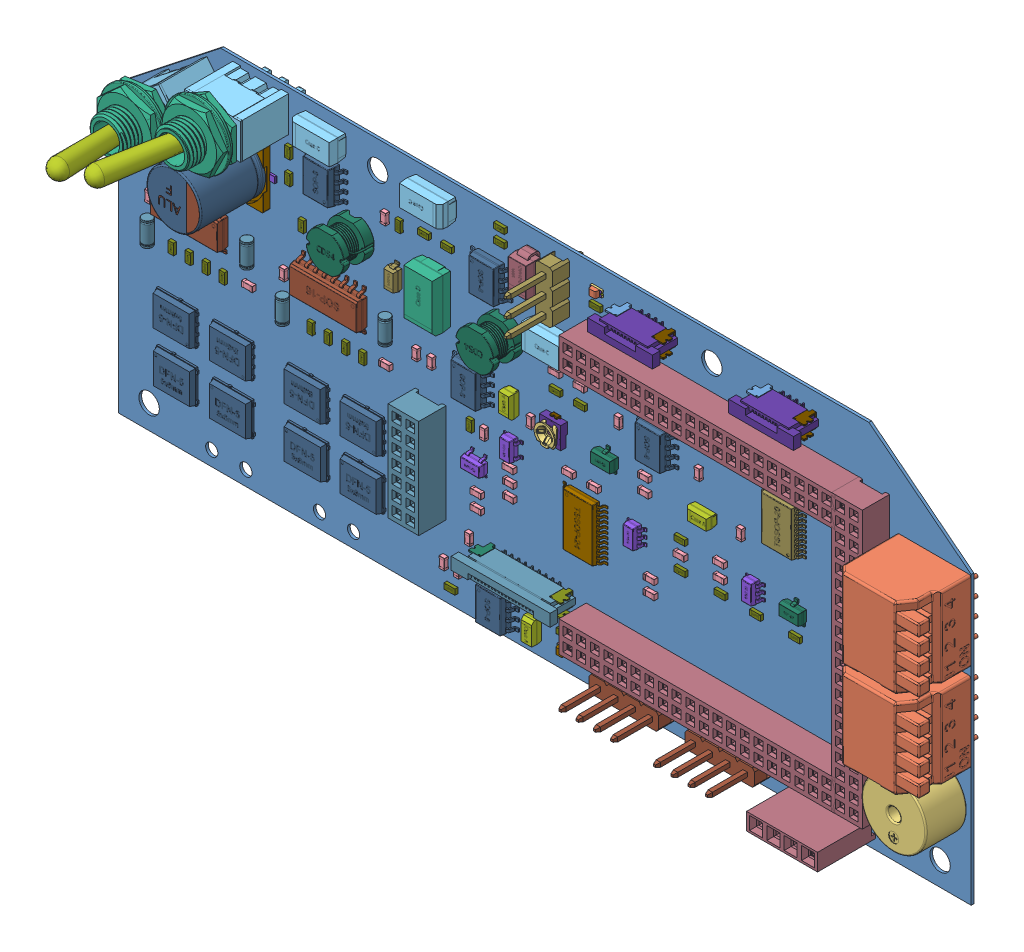
SolidWorks assembly 主板_V1.0, configuration Default. Lengths in mm.
Overall size (126.34 56.68 27.25).
280 component instances, 55 part files, 0 mates.
Components (placement in the parent):
- Board主板_V1.0-1: Board主板_V1.0 [默认] at (0 0 -0.3912) size (125 53.81 0.39)
- S4主板_V1.0-1: S4主板_V1.0 [默认] at origin size (12.1 11.72 11.5)
  - Switch-Piano-DIP-4-1: Switch-Piano-DIP-4 [默认] at (109.7535 13.9265 0.1) x (0 1 0) z (1 0 0) size (11.72 11.5 12.1)
- LS主板_V1.0-1: LS主板_V1.0 [默认] at origin size (9.5 9.5 8)
  - Buzzer_9.5x6-1: Buzzer_9.5x6 [默认] at (115.1492 8.3052 0) x (0 1 0) z (0 0 1) size (9.5 9.5 8)
- C1主板_V1.0-1: C1主板_V1.0 [默认] at origin size (1.6 0.8 0.6)
  - CAP-0603-1: CAP-0603 [默认] at (84.0359 19.9384 0) size (1.6 0.8 0.6)
- C2主板_V1.0-1: C2主板_V1.0 [默认] at origin size (1.6 0.8 0.6)
  - CAP-0603-1: CAP-0603 [默认] at (83.9961 21.94 0) size (1.6 0.8 0.6)
- C3主板_V1.0-1: C3主板_V1.0 [默认] at origin size (1.6 0.8 0.6)
  - CAP-0603-1: CAP-0603 [默认] at (53.135 18.5118 0) size (1.6 0.8 0.6)
- C4主板_V1.0-1: C4主板_V1.0 [默认] at origin size (0.8 1.6 0.6)
  - CAP-0603-1: CAP-0603 [默认] at (49.3838 21.0686 0) x (0 -1 0) z (0 0 1) size (1.6 0.8 0.6)
- C5主板_V1.0-1: C5主板_V1.0 [默认] at origin size (1.6 0.8 0.6)
  - CAP-0603-1: CAP-0603 [默认] at (61.8473 22.2703 0) size (1.6 0.8 0.6)
- C6主板_V1.0-1: C6主板_V1.0 [默认] at origin size (1.6 0.8 0.6)
  - CAP-0603-1: CAP-0603 [默认] at (48.4107 10.9419 0) size (1.6 0.8 0.6)
- C7主板_V1.0-1: C7主板_V1.0 [默认] at origin size (1.6 0.8 0.6)
  - CAP-0603-1: CAP-0603 [默认] at (48.4107 12.9739 0) size (1.6 0.8 0.6)
- C9主板_V1.0-1: C9主板_V1.0 [默认] at origin size (1.6 0.8 0.6)
  - CAP-0603-1: CAP-0603 [默认] at (73.8138 12.8609 0) x (-1 0 0) z (0 0 1) size (1.6 0.8 0.6)
- C10主板_V1.0-1: C10主板_V1.0 [默认] at origin size (1.6 0.8 0.6)
  - CAP-0603-1: CAP-0603 [默认] at (65.5303 22.2703 0) size (1.6 0.8 0.6)
- C11主板_V1.0-1: C11主板_V1.0 [默认] at origin size (1.6 0.8 0.6)
  - CAP-0603-1: CAP-0603 [默认] at (78.1939 19.9384 0) size (1.6 0.8 0.6)
- C12主板_V1.0-1: C12主板_V1.0 [默认] at origin size (1.6 0.8 0.6)
  - CAP-0603-1: CAP-0603 [默认] at (53.1606 16.6494 0) x (-1 0 0) z (0 0 1) size (1.6 0.8 0.6)
- C13主板_V1.0-1: C13主板_V1.0 [默认] at origin size (1.6 0.8 0.6)
  - CAP-0603-1: CAP-0603 [默认] at (53.1606 14.7869 0) x (-1 0 0) z (0 0 1) size (1.6 0.8 0.6)
- C14主板_V1.0-1: C14主板_V1.0 [默认] at origin size (1.6 0.8 0.6)
  - CAP-0603-1: CAP-0603 [默认] at (72.9472 25.3279 0) x (-1 0 0) z (0 0 1) size (1.6 0.8 0.6)
- C15主板_V1.0-1: C15主板_V1.0 [默认] at origin size (1.6 0.8 0.6)
  - CAP-0603-1: CAP-0603 [默认] at (72.9472 27.3235 0) x (-1 0 0) z (0 0 1) size (1.6 0.8 0.6)
- C16主板_V1.0-1: C16主板_V1.0 [默认] at origin size (6 3.2 2.5)
  - CaseC_6032-28-1: CaseC_6032-28 [默认] at (59.5741 38.0994 0) x (1 0 0) z (0 -1 0) size (6 2.5 3.2)
- C17主板_V1.0-1: C17主板_V1.0 [默认] at origin size (1.6 0.8 0.6)
  - CAP-0603-1: CAP-0603 [默认] at (59.8805 34.0662 0) x (-1 0 0) z (0 0 1) size (1.6 0.8 0.6)
- C18主板_V1.0-1: C18主板_V1.0 [默认] at origin size (6 3.2 2.5)
  - CaseC_6032-28-1: CaseC_6032-28 [默认] at (42.1242 47.2178 0) x (-1 0 0) z (0 1 0) size (6 2.5 3.2)
- C19主板_V1.0-1: C19主板_V1.0 [默认] at origin size (0.8 1.6 0.6)
  - CAP-0603-1: CAP-0603 [默认] at (34.855 41.1608 0) x (0 -1 0) z (0 0 1) size (1.6 0.8 0.6)
- C20主板_V1.0-1: C20主板_V1.0 [默认] at origin size (6 3.2 2.5)
  - CaseC_6032-28-1: CaseC_6032-28 [默认] at (25.9589 47.218 0) x (1 0 0) z (0 -1 0) size (6 2.5 3.2)
- C21主板_V1.0-1: C21主板_V1.0 [默认] at origin size (4.3 7.3 2.8)
  - CaseD_7343-31-1: CaseD_7343-31 [默认] at (42.2148 35.4076 0) x (0 1 0) z (1 0 0) size (7.3 2.8 4.3)
- C22主板_V1.0-1: C22主板_V1.0 [默认] at origin size (0.8 1.6 0.6)
  - CAP-0603-1: CAP-0603 [默认] at (43.4872 1.6835 0) x (0 -1 0) z (0 0 1) size (1.6 0.8 0.6)
- C23主板_V1.0-1: C23主板_V1.0 [默认] at origin size (0.8 1.6 0.6)
  - CAP-0603-1: CAP-0603 [默认] at (45.57 1.6835 0) x (0 -1 0) z (0 0 1) size (1.6 0.8 0.6)
- C24主板_V1.0-1: C24主板_V1.0 [默认] at origin size (0.8 1.6 0.6)
  - CAP-0603-1: CAP-0603 [默认] at (47.1994 6.616 0) x (0 -1 0) z (0 0 1) size (1.6 0.8 0.6)
- C25主板_V1.0-1: C25主板_V1.0 [默认] at origin size (0.8 1.6 0.6)
  - CAP-0603-1: CAP-0603 [默认] at (39.4668 26.2255 0) x (0 -1 0) z (0 0 1) size (1.6 0.8 0.6)
- C26主板_V1.0-1: C26主板_V1.0 [默认] at origin size (0.8 1.6 0.6)
  - CAP-0603-1: CAP-0603 [默认] at (41.6766 26.2255 0) x (0 -1 0) z (0 0 1) size (1.6 0.8 0.6)
- C27主板_V1.0-1: C27主板_V1.0 [默认] at origin size (0.8 1.6 0.6)
  - CAP-0603-1: CAP-0603 [默认] at (56.2261 25.9706 0) x (0 1 0) z (0 0 1) size (1.6 0.8 0.6)
- C28主板_V1.0-1: C28主板_V1.0 [默认] at origin size (0.8 1.6 0.6)
  - CAP-0603-1: CAP-0603 [默认] at (69.1039 32.3714 0) x (0 1 0) z (0 0 1) size (1.6 0.8 0.6)
- C29主板_V1.0-1: C29主板_V1.0 [默认] at origin size (0.8 1.6 0.6)
  - CAP-0603-1: CAP-0603 [默认] at (80.8641 31.7112 0) x (0 1 0) z (0 0 1) size (1.6 0.8 0.6)
- C30主板_V1.0-1: C30主板_V1.0 [默认] at origin size (1.6 3.2 1.6)
  - CaseA_3216-18-1: CaseA_3216-18 [默认] at (56.8961 0.2031 0) x (0 -1 0) z (-1 0 0) size (3.2 1.6 1.6)
- C31主板_V1.0-1: C31主板_V1.0 [默认] at origin size (1.6 3.2 1.6)
  - CaseA_3216-18-1: CaseA_3216-18 [默认] at (53.5541 27.152 0) x (0 1 0) z (1 0 0) size (3.2 1.6 1.6)
- C32主板_V1.0-1: C32主板_V1.0 [默认] at origin size (3.2 1.6 1.6)
  - CaseA_3216-18-1: CaseA_3216-18 [默认] at (81.6974 26.898 0) x (1 0 0) z (0 -1 0) size (3.2 1.6 1.6)
- C33主板_V1.0-1: C33主板_V1.0 [默认] at origin size (9.9 8.3 10.2)
  - ALU-F_8.0x8.3x10.2-1: ALU-F_8.0x8.3x10.2 [默认] at (13.7778 37.769 0) x (-1 0 0) z (0 0 1) size (9.9 8.3 10.2)
    - User_Library-ALU-F_Pins_1-1: User_Library-ALU-F_Pins_1 [默认] at origin size (9.9 0.9 0.4)
    - User_Library-ALU-F_Fuss_1-1: User_Library-ALU-F_Fuss_1 [默认] at origin size (8.3 8.3 1)
    - User_Library-ALU-F_K_X_F6rper_1-1: User_Library-ALU-F_K_X_F6rper_1 [默认] at origin size (8 8 9.5)
    - User_Library-ALU-F_Beschriftung_1-1: User_Library-ALU-F_Beschriftung_1 [默认] at origin size (5.99 6.58 0.06)
- C34主板_V1.0-1: C34主板_V1.0 [默认] at origin size (1.6 0.8 0.6)
  - CAP-0603-1: CAP-0603 [默认] at (14.9082 22.5244 0) x (-1 0 0) z (0 0 1) size (1.6 0.8 0.6)
- C35主板_V1.0-1: C35主板_V1.0 [默认] at origin size (0.8 1.6 0.6)
  - CAP-0603-1: CAP-0603 [默认] at (0.2953 26.641 0) x (0 1 0) z (0 0 1) size (1.6 0.8 0.6)
- C36主板_V1.0-1: C36主板_V1.0 [默认] at origin size (1.6 0.8 0.6)
  - CAP-0603-1: CAP-0603 [默认] at (34.9742 22.5244 0) x (-1 0 0) z (0 0 1) size (1.6 0.8 0.6)
- C37主板_V1.0-1: C37主板_V1.0 [默认] at origin size (0.8 1.6 0.6)
  - CAP-0603-1: CAP-0603 [默认] at (20.0311 26.641 0) x (0 1 0) z (0 0 1) size (1.6 0.8 0.6)
- C38主板_V1.0-1: C38主板_V1.0 [默认] at origin size (0.8 1.6 0.6)
  - CAP-0603-1: CAP-0603 [默认] at (87.0363 27.1392 0) x (0 1 0) z (0 0 1) size (1.6 0.8 0.6)
- C39主板_V1.0-1: C39主板_V1.0 [默认] at origin size (1.6 0.8 0.6)
  - CAP-0603-1: CAP-0603 [默认] at (63.5128 34.0662 0) x (-1 0 0) z (0 0 1) size (1.6 0.8 0.6)
- D1主板_V1.0-1: D1主板_V1.0 [默认] at origin size (1.77 3.74 1.47)
  - Diode-SOD123-1: Diode-SOD123 [默认] at (36.4235 34.3916 0) x (0 1 0) z (0 0 1) size (3.74 1.77 1.47)
- D2主板_V1.0-1: D2主板_V1.0 [默认] at origin size (2.8 5.5 2.58)
  - Diode-SMA-1: Diode-SMA [默认] at (56.523 45.4146 0) x (0 1 0) z (0 0 1) size (5.5 2.8 2.58)
- D3主板_V1.0-1: D3主板_V1.0 [默认] at origin size (1.5 3.5 1.5)
  - Diode-SMD-1206-1: Diode-SMD-1206 [默认] at (15.0732 27.0249 0.74) x (0 1 0) z (0 0 1) size (3.5 1.5 1.5)
- D4主板_V1.0-1: D4主板_V1.0 [默认] at origin size (1.5 3.5 1.5)
  - Diode-SMD-1206-1: Diode-SMD-1206 [默认] at (0.4682 22.4783 0.74) x (0 -1 0) z (0 0 1) size (3.5 1.5 1.5)
- D5主板_V1.0-1: D5主板_V1.0 [默认] at origin size (1.5 3.5 1.5)
  - Diode-SMD-1206-1: Diode-SMD-1206 [默认] at (35.3276 27.4059 0.74) x (0 1 0) z (0 0 1) size (3.5 1.5 1.5)
- D6主板_V1.0-1: D6主板_V1.0 [默认] at origin size (1.5 3.5 1.5)
  - Diode-SMD-1206-1: Diode-SMD-1206 [默认] at (20.2802 22.4783 0.74) x (0 -1 0) z (0 0 1) size (3.5 1.5 1.5)
- L2主板_V1.0-1: L2主板_V1.0 [默认] at origin size (5.51 5.35 4.58)
  - Inductor-CD-54-1: Inductor-CD-54 [默认] at (52.2523 35.0283 0) x (-1 0 0) z (0 1 0) size (5.51 4.58 5.35)
- LED1主板_V1.0-1: LED1主板_V1.0 [默认] at origin size (1.7 0.9 0.9)
  - LED-GREEN-0603-1: LED-GREEN-0603 [默认] at (65.797 47.2433 0) x (0 -1 0) z (0 0 1) size (0.9 1.7 0.9)
    - User_Library-LTST-C190GKT_Pad005-1: User_Library-LTST-C190GKT_Pad005 [默认] at origin size (0.35 0.15 0.31)
    - User_Library-LTST-C190GKT_Pad001-1: User_Library-LTST-C190GKT_Pad001 [默认] at origin size (0.9 1.7 0.01)
    - User_Library-LTST-C190GKT_Pad004-1: User_Library-LTST-C190GKT_Pad004 [默认] at origin size (0.35 0.15 0.31)
    - User_Library-LTST-C190GKT_Pad003-1: User_Library-LTST-C190GKT_Pad003 [默认] at origin size (0.8 1.7 0.02)
    - User_Library-LTST-C190GKT_Lens-1: User_Library-LTST-C190GKT_Lens [默认] at origin size (0.9 1.15 0.6)
    - User_Library-LTST-C190GKT_Pad-1: User_Library-LTST-C190GKT_Pad [默认] at origin size (0.9 1.7 0.28)
- LED2主板_V1.0-1: LED2主板_V1.0 [默认] at origin size (1.7 0.9 0.9)
  - LED-BLUE-0603-1: LED-BLUE-0603 [默认] at (60.9346 -0.73 0) x (0 -1 0) z (0 0 1) size (0.9 1.7 0.9)
    - User_Library-LTST-C190TBKT_Pad-1: User_Library-LTST-C190TBKT_Pad [默认] at origin size (0.9 1.7 0.28)
    - User_Library-LTST-C190TBKT_Pad005-1: User_Library-LTST-C190TBKT_Pad005 [默认] at origin size (0.35 0.15 0.31)
    - User_Library-LTST-C190TBKT_Pad001-1: User_Library-LTST-C190TBKT_Pad001 [默认] at origin size (0.9 1.7 0.01)
    - User_Library-LTST-C190TBKT_Pad004-1: User_Library-LTST-C190TBKT_Pad004 [默认] at origin size (0.35 0.15 0.31)
    - User_Library-LTST-C190TBKT_Pad003-1: User_Library-LTST-C190TBKT_Pad003 [默认] at origin size (0.8 1.7 0.02)
    - User_Library-LTST-C190TBKT_Lens-1: User_Library-LTST-C190TBKT_Lens [默认] at origin size (0.9 1.15 0.6)
- MOS1主板_V1.0-1: MOS1主板_V1.0 [默认] at origin size (6.15 5.15 1.02)
  - DFN-5-5x6mm-1: DFN-5-5x6mm [默认] at (15.2407 14.9384 0) x (0 1 0) z (0 0 1) size (5.15 6.15 1.02)
- MOS2主板_V1.0-1: MOS2主板_V1.0 [默认] at origin size (6.15 5.15 1.02)
  - DFN-5-5x6mm-1: DFN-5-5x6mm [默认] at (7.0111 14.9384 0) x (0 1 0) z (0 0 1) size (5.15 6.15 1.02)
- MOS3主板_V1.0-1: MOS3主板_V1.0 [默认] at origin size (6.15 5.15 1.02)
  - DFN-5-5x6mm-1: DFN-5-5x6mm [默认] at (9.7187 3.8068 0) x (0 -1 0) z (0 0 1) size (5.15 6.15 1.02)
- MOS4主板_V1.0-1: MOS4主板_V1.0 [默认] at origin size (6.15 5.15 1.02)
  - DFN-5-5x6mm-1: DFN-5-5x6mm [默认] at (1.4891 3.8068 0) x (0 -1 0) z (0 0 1) size (5.15 6.15 1.02)
- MOS6主板_V1.0-1: MOS6主板_V1.0 [默认] at origin size (6.15 5.15 1.02)
  - DFN-5-5x6mm-1: DFN-5-5x6mm [默认] at (26.1969 14.9384 0) x (0 1 0) z (0 0 1) size (5.15 6.15 1.02)
- MOS5主板_V1.0-1: MOS5主板_V1.0 [默认] at origin size (6.15 5.15 1.02)
  - DFN-5-5x6mm-1: DFN-5-5x6mm [默认] at (34.3923 14.9384 0) x (0 1 0) z (0 0 1) size (5.15 6.15 1.02)
- MOS7主板_V1.0-1: MOS7主板_V1.0 [默认] at origin size (6.15 5.15 1.02)
  - DFN-5-5x6mm-1: DFN-5-5x6mm [默认] at (28.8703 3.8068 0) x (0 -1 0) z (0 0 1) size (5.15 6.15 1.02)
- MOS8主板_V1.0-1: MOS8主板_V1.0 [默认] at origin size (6.15 5.15 1.02)
  - DFN-5-5x6mm-1: DFN-5-5x6mm [默认] at (20.6749 3.8068 0) x (0 -1 0) z (0 0 1) size (5.15 6.15 1.02)
- P1主板_V1.0-1: P1主板_V1.0 [默认] at origin size (10.16 2.5 11.2)
  - Pin-Header-2.54-Single-4-1: Pin-Header-2.54-Single-4 [默认] at (72.3233 -0.6114 0.1) x (-1 0 0) z (0 -1 0) size (10.16 11.2 2.5)
- P2主板_V1.0-1: P2主板_V1.0 [默认] at origin size (10.16 2.5 11.2)
  - Pin-Header-2.54-Single-4-1: Pin-Header-2.54-Single-4 [默认] at (86.2091 -0.6854 0.1) x (1 0 0) z (0 1 0) size (10.16 11.2 2.5)
- P4主板_V1.0-1: P4主板_V1.0 [默认] at origin size (2.5 7.62 11.2)
  - Pin-Header-2.54-Single-3-1: Pin-Header-2.54-Single-3 [默认] at (60.5173 45.2891 0.1) x (0 1 0) z (-1 0 0) size (7.62 11.2 2.5)
- P7主板_V1.0-1: P7主板_V1.0 [默认] at origin size (10.41 2.5 11.7)
  - Female-Header-2.54-Single-4-1: Female-Header-2.54-Single-4 [默认] at (101.4351 -0.6431 0.15) x (-1 0 0) z (0 1 0) size (10.41 11.7 2.5)
- P8主板_V1.0-1: P8主板_V1.0 [默认] at origin size (4.5 14.5 6.8)
  - Female-Header-2.00-Double-14-1: Female-Header-2.00-Double-14 [默认] at (41.4258 14.3265 0.15) x (0 -1 0) z (-1 0 0) size (14.5 6.8 4.5)
- Q1主板_V1.0-1: Q1主板_V1.0 [默认] at origin size (3.01 3 1.3)
  - SOT323-3-1: SOT323-3 [默认] at (67.3957 26.7962 0) x (1 0 0) z (0 -1 0) size (3.01 1.3 3)
- Q2主板_V1.0-1: Q2主板_V1.0 [默认] at origin size (3.01 3 1.3)
  - SOT323-3-1: SOT323-3 [默认] at (95.0055 21.2336 0) x (1 0 0) z (0 -1 0) size (3.01 1.3 3)
- R1主板_V1.0-1: R1主板_V1.0 [默认] at origin size (1.6 0.8 0.46)
  - RES-0603-1: RES-0603 [默认] at (84.0612 17.9323 0.24) x (0 -1 0) z (-1 0 0) size (0.8 0.46 1.6)
- R2主板_V1.0-1: R2主板_V1.0 [默认] at origin size (1.6 0.8 0.46)
  - RES-0603-1: RES-0603 [默认] at (64.8952 -0.7374 0.24) x (0 -1 0) z (-1 0 0) size (0.8 0.46 1.6)
- R3主板_V1.0-1: R3主板_V1.0 [默认] at origin size (1.6 0.8 0.46)
  - RES-0603-1: RES-0603 [默认] at (93.7499 -0.7375 0.24) x (0 1 0) z (1 0 0) size (0.8 0.46 1.6)
- R4主板_V1.0-1: R4主板_V1.0 [默认] at origin size (1.6 0.8 0.46)
  - RES-0603-1: RES-0603 [默认] at (89.2936 17.9323 0.24) x (0 -1 0) z (-1 0 0) size (0.8 0.46 1.6)
- R5主板_V1.0-1: R5主板_V1.0 [默认] at origin size (3.1 3.69 2.19)
  - User_Library-PVZ3A-1: User_Library-PVZ3A [默认] at (59.8788 26.7875 0) size (3.1 3.69 2.19)
    - User_Library-PVZ3A_PVZ3A_base_По_умолчанию-1: User_Library-PVZ3A_PVZ3A_base_По_умолчанию [默认] at origin size (3.1 3.2 1)
    - User_Library-PVZ3A_Pin1_По_умолчанию-1: User_Library-PVZ3A_Pin1_По_умолчанию [默认] at (0 1.14 0) size (1 0.7 0.65)
    - User_Library-PVZ3A_Pin2_По_умолчанию-1: User_Library-PVZ3A_Pin2_По_умолчанию [默认] at (0.875 -1.15 0) x (-1 0 0) z (0 0 1) size (0.75 0.7 0.65)
    - User_Library-PVZ3A_Pin2_По_умолчанию_2-1: User_Library-PVZ3A_Pin2_По_умолчанию_2 [默认] at (-0.875 -1.15 0) x (-1 0 0) z (0 0 1) size (0.75 0.7 0.65)
    - User_Library-PVZ3A_PVZ3A_res_По_умолчанию-1: User_Library-PVZ3A_PVZ3A_res_По_умолчанию [默认] at (0 0 0.9) size (3 3.08 1.33)
    - User_Library-PVZ3A_PVZ3A_con_По_умолчанию-1: User_Library-PVZ3A_PVZ3A_con_По_умолчанию [默认] at (0 0 1.22) size (0.58 0.58 0.75)
- R6主板_V1.0-1: R6主板_V1.0 [默认] at origin size (1.6 0.8 0.46)
  - RES-0603-1: RES-0603 [默认] at (78.1794 21.894 0.24) x (0 -1 0) z (-1 0 0) size (0.8 0.46 1.6)
- R7主板_V1.0-1: R7主板_V1.0 [默认] at origin size (1.6 0.8 0.46)
  - RES-0603-1: RES-0603 [默认] at (78.2192 17.9323 0.24) x (0 -1 0) z (-1 0 0) size (0.8 0.46 1.6)
- R8主板_V1.0-1: R8主板_V1.0 [默认] at origin size (0.8 1.6 0.46)
  - RES-0603-1: RES-0603 [默认] at (20.7266 39.0272 0.24) x (-1 0 0) z (0 1 0) size (0.8 0.46 1.6)
- R9主板_V1.0-1: R9主板_V1.0 [默认] at origin size (1.6 0.8 0.46)
  - RES-0603-1: RES-0603 [默认] at (51.727 48.2592 0.24) x (0 -1 0) z (-1 0 0) size (0.8 0.46 1.6)
- R10主板_V1.0-1: R10主板_V1.0 [默认] at origin size (1.6 0.8 0.46)
  - RES-0603-1: RES-0603 [默认] at (51.727 46.4057 0.24) x (0 -1 0) z (-1 0 0) size (0.8 0.46 1.6)
- R11主板_V1.0-1: R11主板_V1.0 [默认] at origin size (0.8 1.6 0.46)
  - RES-0603-1: RES-0603 [默认] at (20.7265 42.4052 0.24) x (1 0 0) z (0 -1 0) size (0.8 0.46 1.6)
- R12主板_V1.0-1: R12主板_V1.0 [默认] at origin size (1.6 0.8 0.46)
  - RES-0603-1: RES-0603 [默认] at (43.9802 41.9355 0.24) x (0 1 0) z (1 0 0) size (0.8 0.46 1.6)
- R13主板_V1.0-1: R13主板_V1.0 [默认] at origin size (0.8 1.6 0.46)
  - RES-0603-1: RES-0603 [默认] at (36.8807 41.1355 0.24) x (-1 0 0) z (0 1 0) size (0.8 0.46 1.6)
- R14主板_V1.0-1: R14主板_V1.0 [默认] at origin size (1.6 0.8 0.46)
  - RES-0603-1: RES-0603 [默认] at (40.602 41.9355 0.24) x (0 1 0) z (1 0 0) size (0.8 0.46 1.6)
- R15主板_V1.0-1: R15主板_V1.0 [默认] at origin size (1.6 0.8 0.46)
  - RES-0603-1: RES-0603 [默认] at (44.488 -1.1431 0.24) x (0 -1 0) z (-1 0 0) size (0.8 0.46 1.6)
- R16主板_V1.0-1: R16主板_V1.0 [默认] at origin size (1.6 0.8 0.46)
  - RES-0603-1: RES-0603 [默认] at (65.7725 45.3128 0.24) x (0 -1 0) z (-1 0 0) size (0.8 0.46 1.6)
- R17主板_V1.0-1: R17主板_V1.0 [默认] at origin size (1.6 0.8 0.46)
  - RES-0603-1: RES-0603 [默认] at (60.9472 1.4223 0.24) x (0 -1 0) z (-1 0 0) size (0.8 0.46 1.6)
- R18主板_V1.0-1: R18主板_V1.0 [默认] at origin size (0.8 1.6 0.46)
  - RES-0603-1: RES-0603 [默认] at (47.3312 21.0433 0.24) x (-1 0 0) z (0 1 0) size (0.8 0.46 1.6)
- R19主板_V1.0-1: R19主板_V1.0 [默认] at origin size (0.8 1.6 0.46)
  - RES-0603-1: RES-0603 [默认] at (11.1361 21.7298 0.24) x (-1 0 0) z (0 1 0) size (0.8 0.46 1.6)
- R20主板_V1.0-1: R20主板_V1.0 [默认] at origin size (0.8 1.6 0.46)
  - RES-0603-1: RES-0603 [默认] at (8.6385 21.7298 0.24) x (-1 0 0) z (0 1 0) size (0.8 0.46 1.6)
- R21主板_V1.0-1: R21主板_V1.0 [默认] at origin size (1.6 0.8 0.46)
  - RES-0603-1: RES-0603 [默认] at (2.832 33.8838 0.24) x (0 -1 0) z (-1 0 0) size (0.8 0.46 1.6)
- R22主板_V1.0-1: R22主板_V1.0 [默认] at origin size (1.6 0.8 0.46)
  - RES-0603-1: RES-0603 [默认] at (6.2612 33.8837 0.24) x (0 1 0) z (1 0 0) size (0.8 0.46 1.6)
- R23主板_V1.0-1: R23主板_V1.0 [默认] at origin size (0.8 1.6 0.46)
  - RES-0603-1: RES-0603 [默认] at (6.1408 21.7298 0.24) x (-1 0 0) z (0 1 0) size (0.8 0.46 1.6)
- R24主板_V1.0-1: R24主板_V1.0 [默认] at origin size (0.8 1.6 0.46)
  - RES-0603-1: RES-0603 [默认] at (3.6432 21.7298 0.24) x (-1 0 0) z (0 1 0) size (0.8 0.46 1.6)
- R25主板_V1.0-1: R25主板_V1.0 [默认] at origin size (0.8 1.6 0.46)
  - RES-0603-1: RES-0603 [默认] at (31.5831 21.7291 0.24) x (-1 0 0) z (0 1 0) size (0.8 0.46 1.6)
- R26主板_V1.0-1: R26主板_V1.0 [默认] at origin size (0.8 1.6 0.46)
  - RES-0603-1: RES-0603 [默认] at (29.0479 21.7298 0.24) x (-1 0 0) z (0 1 0) size (0.8 0.46 1.6)
- R27主板_V1.0-1: R27主板_V1.0 [默认] at origin size (0.8 1.6 0.46)
  - RES-0603-1: RES-0603 [默认] at (22.6932 34.0481 0.24) x (-1 0 0) z (0 1 0) size (0.8 0.46 1.6)
- R28主板_V1.0-1: R28主板_V1.0 [默认] at origin size (0.8 1.6 0.46)
  - RES-0603-1: RES-0603 [默认] at (24.9793 34.048 0.24) x (1 0 0) z (0 -1 0) size (0.8 0.46 1.6)
- R29主板_V1.0-1: R29主板_V1.0 [默认] at origin size (0.8 1.6 0.46)
  - RES-0603-1: RES-0603 [默认] at (26.5127 21.7298 0.24) x (-1 0 0) z (0 1 0) size (0.8 0.46 1.6)
- R30主板_V1.0-1: R30主板_V1.0 [默认] at origin size (0.8 1.6 0.46)
  - RES-0603-1: RES-0603 [默认] at (23.9775 21.7298 0.24) x (-1 0 0) z (0 1 0) size (0.8 0.46 1.6)
- R31主板_V1.0-1: R31主板_V1.0 [默认] at origin size (1.6 0.8 0.46)
  - RES-0603-1: RES-0603 [默认] at (59.8803 31.6483 0.24) x (0 -1 0) z (-1 0 0) size (0.8 0.46 1.6)
- R32主板_V1.0-1: R32主板_V1.0 [默认] at origin size (1.6 0.8 0.46)
  - RES-0603-1: RES-0603 [默认] at (63.5126 31.6483 0.24) x (0 -1 0) z (-1 0 0) size (0.8 0.46 1.6)
- R33主板_V1.0-1: R33主板_V1.0 [默认] at origin size (1.6 0.8 0.46)
  - RES-0603-1: RES-0603 [默认] at (95.034 17.9323 0.24) x (0 -1 0) z (-1 0 0) size (0.8 0.46 1.6)
- S1主板_V1.0-1: S1主板_V1.0 [默认] at origin size (17.73 16.75 27.25)
  - SW-SMTS-102-1: SW-SMTS-102 [默认] at (10.2794 45.0706 -8.5) x (0.788011 0.615661 0) z (0 0 1) size (15.11 9.45 27.25)
    - SW-SMTS-102-1-1: SW-SMTS-102-1 [默认] at (-2.742 1.0938 9.095) size (8.2 5.35 10.79)
    - SW-SMTS-102-2-1: SW-SMTS-102-2 [默认] at (-2.742 1.0938 24.585) size (9.45 9.45 6.14)
    - SW-SMTS-102-3-1: SW-SMTS-102-3 [默认] at (-3.1483 1.0938 18.8532) x (-0.970296 0 -0.241922) z (0 1 0) size (10.65 19.74 3.81)
- S2主板_V1.0-1: S2主板_V1.0 [默认] at origin size (15.11 9.45 27.25)
  - SW-SMTS-102-1: SW-SMTS-102 [默认] at (14.2145 48.6156 -8.5) x (-1 0 0) z (0 0 1) size (15.11 9.45 27.25)
    - SW-SMTS-102-1-1: SW-SMTS-102-1 [默认] at (-2.742 1.0938 9.095) size (8.2 5.35 10.79)
    - SW-SMTS-102-2-1: SW-SMTS-102-2 [默认] at (-2.742 1.0938 24.585) size (9.45 9.45 6.14)
    - SW-SMTS-102-3-1: SW-SMTS-102-3 [默认] at (-3.1483 1.0938 18.8532) x (-0.970296 0 -0.241922) z (0 1 0) size (10.65 19.74 3.81)
- S3主板_V1.0-1: S3主板_V1.0 [默认] at origin size (12.1 11.72 11.5)
  - Switch-Piano-DIP-4-1: Switch-Piano-DIP-4 [默认] at (109.7535 26.7535 0.1) x (0 1 0) z (1 0 0) size (11.72 11.5 12.1)
- U1主板_V1.0-1: U1主板_V1.0 [默认] at origin size (2.8 2.9 1.45)
  - SOT23-5-1: SOT23-5 [默认] at (53.5011 21.4624 0) x (0 -1 0) z (0 0 1) size (2.9 2.8 1.45)
- U2主板_V1.0-1: U2主板_V1.0 [默认] at origin size (2.9 2.8 1.45)
  - SOT23-5-1: SOT23-5 [默认] at (48.4234 16.7355 0) size (2.9 2.8 1.45)
- U3主板_V1.0-1: U3主板_V1.0 [默认] at origin size (2.8 2.9 1.45)
  - SOT23-5-1: SOT23-5 [默认] at (88.9642 21.1066 0) x (0 1 0) z (0 0 1) size (2.9 2.8 1.45)
- U4主板_V1.0-1: U4主板_V1.0 [默认] at origin size (6.55 7.9 1.2)
  - TSSOP-24-1: TSSOP-24 [默认] at (64.0191 17.4492 0) x (0 -1 0) z (0 0 1) size (7.9 6.55 1.2)
- U5主板_V1.0-1: U5主板_V1.0 [默认] at origin size (2.8 2.9 1.45)
  - SOT23-5-1: SOT23-5 [默认] at (71.6304 19.4563 0) x (0 1 0) z (0 0 1) size (2.9 2.8 1.45)
- U6主板_V1.0-1: U6主板_V1.0 [默认] at origin size (6 4.9 1.75)
  - SOP-8-1: SOP-8 [默认] at (26.173 41.9601 0) x (0 1 0) z (0 0 1) size (4.9 6 1.75)
- U7主板_V1.0-1: U7主板_V1.0 [默认] at origin size (6 4.9 1.75)
  - SOP-8-1: SOP-8 [默认] at (50.3285 41.5536 0) x (0 -1 0) z (0 0 1) size (4.9 6 1.75)
- U8主板_V1.0-1: U8主板_V1.0 [默认] at origin size (6 4.9 1.75)
  - SOP-8-1: SOP-8 [默认] at (51.3191 0.2532 0) x (0 -1 0) z (0 0 1) size (4.9 6 1.75)
- U9主板_V1.0-1: U9主板_V1.0 [默认] at origin size (6 4.9 1.75)
  - SOP-8-1: SOP-8 [默认] at (47.6758 26.9494 0) x (0 -1 0) z (0 0 1) size (4.9 6 1.75)
- U11主板_V1.0-1: U11主板_V1.0 [默认] at origin size (10 6 1.75)
  - SOP-16-1: SOP-16 [默认] at (6.8071 27.7129 0) x (-1 0 0) z (0 0 1) size (10 6 1.75)
- U12主板_V1.0-1: U12主板_V1.0 [默认] at origin size (10 6 1.75)
  - SOP-16-1: SOP-16 [默认] at (27.2033 27.7129 0) x (-1 0 0) z (0 0 1) size (10 6 1.75)
- U13主板_V1.0-1: U13主板_V1.0 [默认] at origin size (6.5 6.6 1.2)
  - TSSOP-20-1: TSSOP-20 [默认] at (93.1417 31.5213 0) x (-1 0 0) z (0 0 1) size (6.5 6.6 1.2)
- CN2主板_V1.0-1: CN2主板_V1.0 [默认] at origin size (4.5 40.5 6.8)
  - Female-Header-2.00-Double-40-1: Female-Header-2.00-Double-40 [默认] at (106.4498 22.5736 0.15) x (0 -1 0) z (-1 0 0) size (40.5 6.8 4.5)
- CN3主板_V1.0-1: CN3主板_V1.0 [默认] at origin size (40.5 4.5 6.8)
  - Female-Header-2.00-Double-40-1: Female-Header-2.00-Double-40 [默认] at (84.4773 4.5571 0.15) x (1 0 0) z (0 -1 0) size (40.5 6.8 4.5)
- CN1主板_V1.0-1: CN1主板_V1.0 [默认] at origin size (40.5 4.5 6.8)
  - Female-Header-2.00-Double-40-1: Female-Header-2.00-Double-40 [默认] at (84.4773 40.557 0.15) x (1 0 0) z (0 -1 0) size (40.5 6.8 4.5)
- P3主板_V1.0-1: P3主板_V1.0 [默认] at origin size (14.5 2.54 4.64)
  - Header-FPC-ZIF-SMD-Vertical_Single-0.5-18-1: Header-FPC-ZIF-SMD-Vertical_Single-0.5-18 [默认] at (56.1085 5.2731 4.08) size (14.5 2.54 4.64)
    - ffc_fpc_affc20-18-050-shb-t_01-1: ffc_fpc_affc20-18-050-shb-t_01 [默认] at origin size (14.5 2.54 4.55)
    - ffc_fpc_affc20-18-050-shb-t_02-1: ffc_fpc_affc20-18-050-shb-t_02 [默认] at origin size (1.7 2.05 2.6)
    - ffc_fpc_affc20-18-050-shb-t_03-1: ffc_fpc_affc20-18-050-shb-t_03 [默认] at origin size (1.7 2.05 2.6)
- P5主板_V1.0-1: P5主板_V1.0 [默认] at origin size (9.5 2.54 4.64)
  - Header-FPC-ZIF-SMD-Vertical_Single-0.5-8-1: Header-FPC-ZIF-SMD-Vertical_Single-0.5-8 [默认] at (73.6202 47.7766 4.08) x (-1 0 0) z (0 0 1) size (9.5 2.54 4.64)
    - ffc_fpc_affc20-08-050-shb-t_01-1: ffc_fpc_affc20-08-050-shb-t_01 [默认] at origin size (9.5 2.54 4.55)
    - ffc_fpc_affc20-08-050-shb-t_02-1: ffc_fpc_affc20-08-050-shb-t_02 [默认] at origin size (1.7 2.05 2.6)
    - ffc_fpc_affc20-08-050-shb-t_03-1: ffc_fpc_affc20-08-050-shb-t_03 [默认] at origin size (1.7 2.05 2.6)
- P6主板_V1.0-1: P6主板_V1.0 [默认] at origin size (9.5 2.54 4.64)
  - Header-FPC-ZIF-SMD-Vertical_Single-0.5-8-1: Header-FPC-ZIF-SMD-Vertical_Single-0.5-8 [默认] at (94.2958 47.7766 4.08) x (-1 0 0) z (0 0 1) size (9.5 2.54 4.64)
    - ffc_fpc_affc20-08-050-shb-t_01-1: ffc_fpc_affc20-08-050-shb-t_01 [默认] at origin size (9.5 2.54 4.55)
    - ffc_fpc_affc20-08-050-shb-t_02-1: ffc_fpc_affc20-08-050-shb-t_02 [默认] at origin size (1.7 2.05 2.6)
    - ffc_fpc_affc20-08-050-shb-t_03-1: ffc_fpc_affc20-08-050-shb-t_03 [默认] at origin size (1.7 2.05 2.6)
- L1主板_V1.0-1: L1主板_V1.0 [默认] at origin size (5.51 5.35 4.58)
  - Inductor-CD-54-1: Inductor-CD-54 [默认] at (30.3087 36.5736 0) x (1 0 0) z (0 -1 0) size (5.51 4.58 5.35)
- C8主板_V1.0-1: C8主板_V1.0 [默认] at origin size (1.6 0.8 0.6)
  - CAP-0603-1: CAP-0603 [默认] at (73.8138 14.782 0) x (-1 0 0) z (0 0 1) size (1.6 0.8 0.6)
- U10主板_V1.0-1: U10主板_V1.0 [默认] at origin size (6 4.9 1.75)
  - SOP-8-1: SOP-8 [默认] at (74.7125 32.562 0) x (0 -1 0) z (0 0 1) size (4.9 6 1.75)
